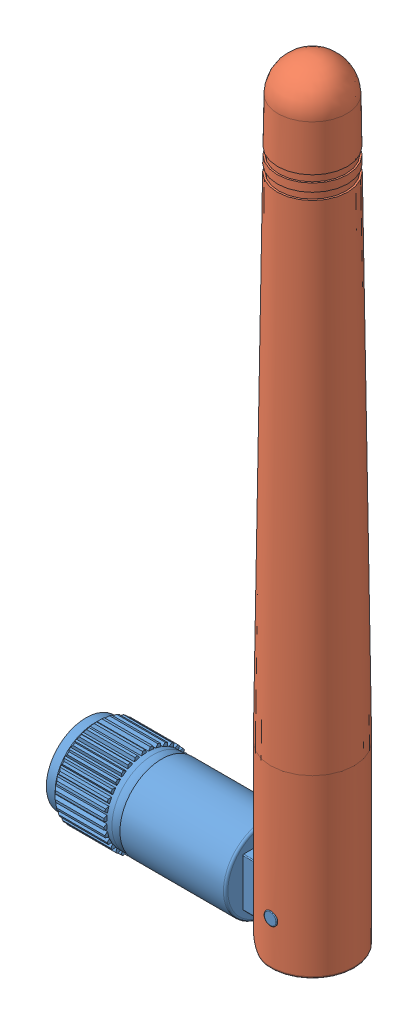
SolidWorks assembly Antenna assy, configuration 0. Lengths in mm.
Overall size (30.45 87.5 9.98).
2 component instances, 2 part files, 8 mates.
Components (placement in the parent):
- Antenna base-1: Antenna base [По умолчанию] at origin size (28.45 9.98 9.98)
- Antenna top-1: Antenna top [По умолчанию] at (25.7 -5 0) x (0 1 0) z (0 0 1) size (87.5 9.5 9.5)
Mates (geometry in assembly coordinates):
- Совпадение1: coincident: plane of Antenna base-1 through (0 0 0) normal (0 0 1); plane of assembly through (0 0 0) normal (0 0 1)
- Совпадение2: coincident: plane of Antenna base-1 through (0 0 0) normal (0 1 0); plane of assembly through (0 0 0) normal (0 1 0)
- Совпадение3: coincident: plane of Antenna base-1 through (0 0 0) normal (1 0 0); plane of assembly through (0 0 0) normal (1 0 0)
- Совпадение4: coincident: plane of Antenna top-1 through (20.7 0 0) normal (0 0 1); plane of assembly through (0 0 0) normal (0 0 1)
- Концентричный1: concentric: cylinder of Antenna base-1 through (25.7 0 4.8) axis (0 0 -1) radius 0.75; cylinder of Antenna top-1 through (25.7 0 -4.75) axis (0 0 1) radius 0.75
- Параллельность1: planar angle = 1.570796 rad aligned: plane of Antenna top-1 through (25.7 -5 0) normal (-1 0 0)
- Угол1: planar angle = 0.785398 rad: plane of Antenna top-1; plane of assembly through (0 0 0) normal (0 1 0)
- Угол2: planar angle = 1.570796 rad: plane of Antenna top-1; plane of assembly through (0 0 0) normal (0 1 0)
